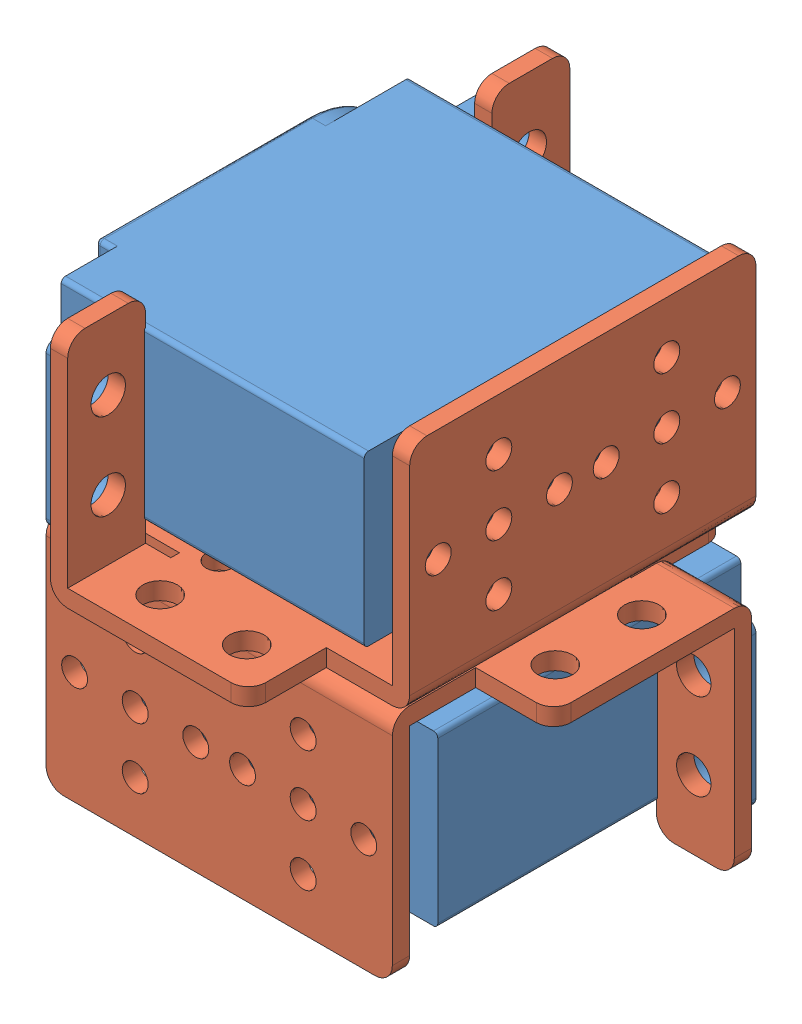
SolidWorks assembly 六足舵机装配图（反装）, configuration 默认. Lengths in mm.
Overall size (58 54 58).
6 component instances, 2 part files, 3 mates.
Components (placement in the parent):
- 舵机与支架装配图（反装）-1: 舵机与支架装配图（反装） [默认] at (-7.582 -7.3466 0.6333) size (58 27 48.1)
  - MG995舵机-2: MG995舵机 [默认] at (-1.9429 16.1092 -14.4333) size (54 19.5 43)
  - 舵机支架-2: 舵机支架 [默认] at (9.5712 21.0726 4.9167) x (-1 0 0) z (0 -1 0) size (58 39.5 27)
- 舵机与支架装配图（反装）-2: 舵机与支架装配图（反装） [默认] at (-2.6776 34.7987 -4.2712) x (0 0 1) z (1 0 0) size (58 27 48.1)
  - MG995舵机-2: MG995舵机 [默认] at (-1.9429 16.1092 -14.4333) size (54 19.5 43)
  - 舵机支架-2: 舵机支架 [默认] at (9.5712 21.0726 4.9167) x (-1 0 0) z (0 -1 0) size (58 39.5 27)
Mates (geometry in assembly coordinates):
- 重合1: coincident anti-aligned: plane of 舵机与支架装配图（反装）-1/舵机支架-2 through (28.9892 13.726 14.6741) normal (0 1 0); plane of 舵机与支架装配图（反装）-2/舵机支架-2 through (11.3633 13.726 32.3) normal (0 -1 0)
- 同心1: concentric aligned: circle of 舵机与支架装配图（反装）-1/舵机支架-2; axis of 舵机与支架装配图（反装）-2/舵机支架-2 through (1.9892 15.726 5.3) axis (0 -1 0)
- 同心2: concentric anti-aligned: circle of 舵机与支架装配图（反装）-1/舵机支架-2; circle of 舵机与支架装配图（反装）-2/舵机支架-2
